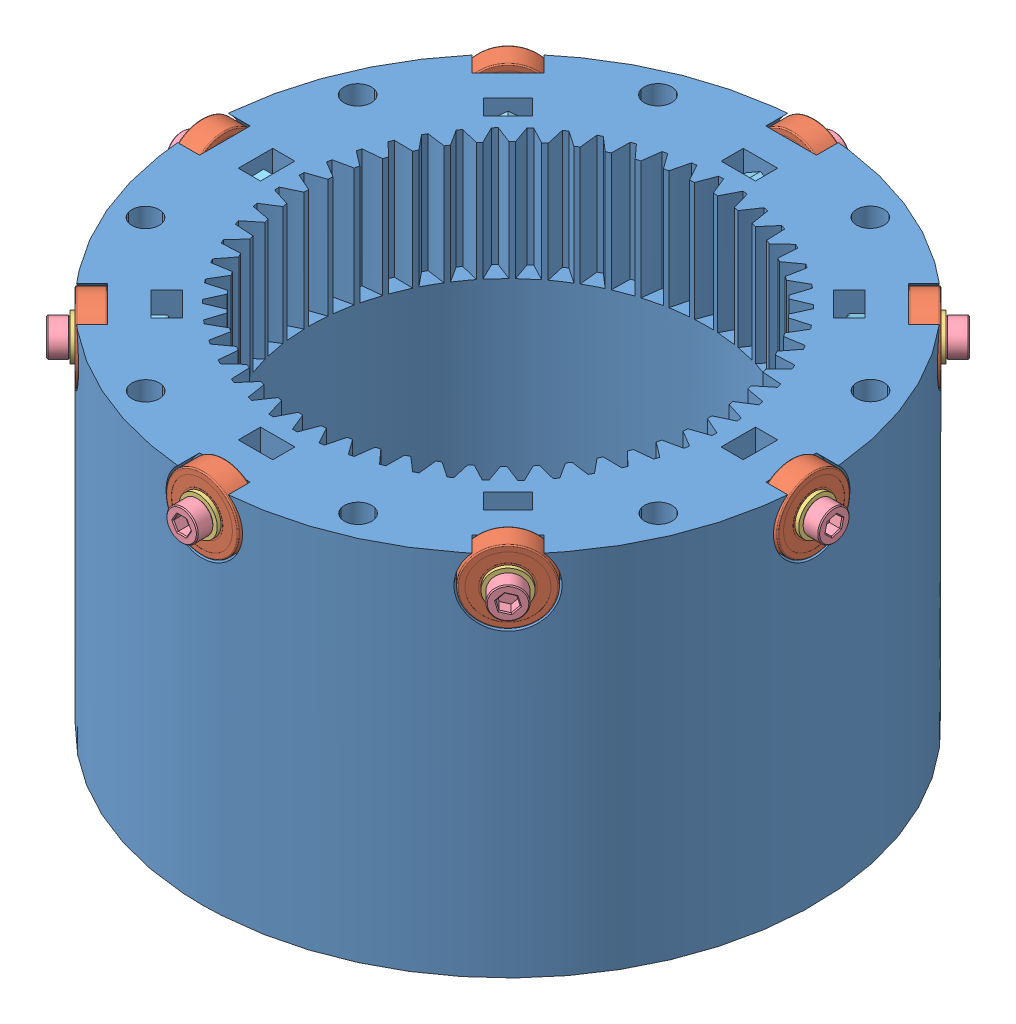
SolidWorks assembly plantery reducer, configuration Default. Lengths in mm.
Overall size (170.6 101.1 170.6).
33 component instances, 5 part files, 96 mates.
Components (placement in the parent):
- updated_1M2A-1: updated_1M2A [Predeterminado] at (8.2264 44.0643 176.7779) size (160 96.57 160)
- 607ZZ-1: 607ZZ [Default] at (60.5523 132.5643 124.452) x (0.707107 0 -0.707107) z (0.642402 -0.417898 0.642402) size (6 19 19)
- 607ZZ-2: 607ZZ [Default] at (8.2264 132.5643 256.7779) x (0 0 -1) z (0.989529 -0.144332 0) size (6 19 19)
- 607ZZ-3: 607ZZ [Default] at (60.5523 132.5643 229.1038) x (0.707107 0 0.707107) z (0.112875 -0.987177 -0.112875) size (6 19 19)
- 607ZZ-4: 607ZZ [Default] at (82.2264 132.5643 176.7779) x (1 0 0) z (0 -0.988196 -0.153195) size (6 19 19)
- 607ZZ-5: 607ZZ [Default] at (-48.3421 132.5643 120.2094) x (0.707107 0 0.707107) z (-0.707107 0 0.707107) size (6 19 19)
- 607ZZ-6: 607ZZ [Default] at (-71.7736 132.5643 176.7779) size (6 19 19)
- 607ZZ-7: 607ZZ [Default] at (-48.3421 132.5643 233.3465) x (0.707107 0 -0.707107) z (0.660156 -0.358314 0.660156) size (6 19 19)
- 607ZZ-8: 607ZZ [Default] at (8.2264 132.5643 96.7779) x (0 0 1) z (-0.997892 0.064889 0) size (6 19 19)
- M5 Rivet Nut-4: M5 Rivet Nut [Default] at (65.5021 132.5643 119.5023) x (0.5 0.707107 0.5) z (0.5 -0.707107 0.5) size (10 13 10)
- M5 Rivet Nut-5: M5 Rivet Nut [Default] at (8.2264 132.5643 95.7779) x (1 0 0) z (0 -1 0) size (10 13 10)
- M5 Rivet Nut-6: M5 Rivet Nut [Default] at (-49.0492 132.5643 119.5023) x (0.5 -0.707107 -0.5) z (-0.5 -0.707107 0.5) size (10 13 10)
- M5 Rivet Nut-7: M5 Rivet Nut [Default] at (89.2264 132.5643 176.7779) x (0 1 0) z (0 0 1) size (10 13 10)
- M5 Rivet Nut-8: M5 Rivet Nut [Default] at (8.2264 132.5643 257.7779) x (1 0 0) z (0 1 0) size (10 13 10)
- M5 Rivet Nut-9: M5 Rivet Nut [Default] at (65.5021 132.5643 234.0536) x (0.5 0.707107 -0.5) z (-0.5 0.707107 0.5) size (10 13 10)
- M5 Rivet Nut-10: M5 Rivet Nut [Default] at (-49.0492 132.5643 234.0536) x (0.5 -0.707107 0.5) z (0.5 0.707107 0.5) size (10 13 10)
- M5 Rivet Nut-11: M5 Rivet Nut [Default] at (-72.7736 132.5643 176.7779) x (0 -1 0) z (0 0 1) size (10 13 10)
- M5x20-1: M5x20 [Predeterminado] at (8.2264 132.5643 91.4779) x (1 0 0) z (0 -1 0) size (8.2 24.3 8.2)
- M5x20-2: M5x20 [Predeterminado] at (68.5426 132.5643 116.4617) x (0.5 0.707107 0.5) z (0.5 -0.707107 0.5) size (8.2 24.3 8.2)
- M5x20-3: M5x20 [Predeterminado] at (-52.0898 132.5643 116.4617) x (0.5 -0.707107 -0.5) z (-0.5 -0.707107 0.5) size (8.2 24.3 8.2)
- M5x20-4: M5x20 [Predeterminado] at (93.5264 132.5643 176.7779) x (0 0.693084 0.720857) z (0 -0.720857 0.693084) size (8.2 24.3 8.2)
- M5x20-5: M5x20 [Predeterminado] at (-77.0736 132.5643 176.7779) x (0 -1 0) z (0 0 1) size (8.2 24.3 8.2)
- M5x20-6: M5x20 [Predeterminado] at (8.2264 132.5643 262.0779) x (1 0 0) z (0 1 0) size (8.2 24.3 8.2)
- M5x20-7: M5x20 [Predeterminado] at (-52.0898 132.5643 237.0941) x (0.5 -0.707107 0.5) z (0.5 0.707107 0.5) size (8.2 24.3 8.2)
- M5x20-8: M5x20 [Predeterminado] at (68.5426 132.5643 237.0941) x (0.5 0.707107 -0.5) z (-0.5 0.707107 0.5) size (8.2 24.3 8.2)
- M5 Lock-1: M5 Lock [Predeterminado] at (8.2264 132.5643 242.7779) x (-0.651073 0.759015 0) z (-0.759015 -0.651073 0) size (7.85 4.3 9.06)
- M5 Lock-2: M5 Lock [Predeterminado] at (74.2264 132.5643 176.7779) x (0 0.785093 -0.619378) z (0 0.619378 0.785093) size (7.85 4.3 9.06)
- M5 Lock-3: M5 Lock [Predeterminado] at (54.8955 132.5643 223.447) x (-0.706997 0.017601 0.706997) z (-0.012446 -0.999845 0.012446) size (7.85 4.3 9.06)
- M5 Lock-4: M5 Lock [Predeterminado] at (54.8955 132.5643 130.1089) x (0.698414 -0.156315 0.698414) z (-0.110531 -0.987707 -0.110531) size (7.85 4.3 9.06)
- M5 Lock-5: M5 Lock [Predeterminado] at (-57.7736 132.5643 176.7779) x (0 -0.99951 -0.031292) z (0 -0.031292 0.99951) size (7.85 4.3 9.06)
- M5 Lock-7: M5 Lock [Predeterminado] at (-38.4426 132.5643 130.1089) x (-0.707095 0.005803 0.707095) z (0.004104 0.999983 -0.004104) size (7.85 4.3 9.06)
- M5 Lock-8: M5 Lock [Predeterminado] at (8.2264 132.5643 110.7779) x (1 0 0) z (0 -1 0) size (7.85 4.3 9.06)
- M5 Lock-9: M5 Lock [Predeterminado] at (-38.4426 132.5643 223.447) x (0.69165 0.207946 0.69165) z (-0.14704 0.97814 -0.14704) size (7.85 4.3 9.06)
Mates (geometry in assembly coordinates):
- Concentric8: concentric anti-aligned: cylinder of planetary gear-3 through (25.4855 152.6206 204.9049) axis (0 -1 0) radius 5.5
- Concentric9: concentric anti-aligned: cylinder of planetary gear-1 through (-24.7736 152.6206 177.6616) axis (0 -1 0) radius 5.5
- Concentric10: concentric anti-aligned: cylinder of planetary gear-2 through (23.9555 152.6206 147.7677) axis (0 -1 0) radius 5.5
- Concentric12: concentric anti-aligned: cylinder of updated_1M2A-1 through (-47.8741 132.5643 176.7779) axis (-1 0 0) radius 3.5; cylinder of 607ZZ-6 through (-65.7736 132.5643 176.7779) axis (1 0 0) radius 3.5
- Coincident13: coincident anti-aligned: plane of updated_1M2A-1 through (-65.7736 132.5643 176.7779) normal (-1 0 0); plane of 607ZZ-6 through (-65.7736 136.3643 176.7779) normal (1 0 0)
- Concentric13: concentric anti-aligned: cylinder of updated_1M2A-1 through (-31.4426 132.5643 216.447) axis (-0.707107 0 0.707107) radius 3.5; cylinder of 607ZZ-7 through (-44.0995 132.5643 229.1038) axis (0.707107 0 -0.707107) radius 3.5
- Coincident14: coincident anti-aligned: plane of updated_1M2A-1 through (-44.0995 132.5643 229.1038) normal (-0.707107 0 0.707107); plane of 607ZZ-7 through (-43.1367 136.112 230.0666) normal (0.707107 0 -0.707107)
- Concentric14: concentric anti-aligned: cylinder of updated_1M2A-1 through (8.2264 132.5643 232.8784) axis (0 0 1) radius 3.5; cylinder of 607ZZ-2 through (8.2264 132.5643 250.7779) axis (0 0 -1) radius 3.5
- Coincident15: coincident anti-aligned: plane of updated_1M2A-1 through (8.2264 132.5643 250.7779) normal (0 0 1); plane of 607ZZ-2 through (8.7749 136.3245 250.7779) normal (0 0 -1)
- Concentric15: concentric aligned: cylinder of updated_1M2A-1 through (47.8955 132.5643 216.447) axis (0.707107 0 0.707107) radius 3.5; cylinder of 607ZZ-3 through (64.795 132.5643 233.3465) axis (0.707107 0 0.707107) radius 3.5
- Coincident16: coincident anti-aligned: plane of updated_1M2A-1 through (60.5523 132.5643 229.1038) normal (0.707107 0 0.707107); plane of 607ZZ-3 through (56.769 131.6991 232.8872) normal (-0.707107 0 -0.707107)
- Concentric16: concentric aligned: cylinder of updated_1M2A-1 through (64.3269 132.5643 176.7779) axis (1 0 0) radius 3.5; cylinder of 607ZZ-4 through (88.2264 132.5643 176.7779) axis (1 0 0) radius 3.5
- Coincident17: coincident anti-aligned: plane of updated_1M2A-1 through (82.2264 132.5643 176.7779) normal (1 0 0); plane of 607ZZ-4 through (82.2264 131.734 182.134) normal (-1 0 0)
- Concentric17: concentric aligned: cylinder of updated_1M2A-1 through (47.8955 132.5643 137.1089) axis (0.707107 0 -0.707107) radius 3.5; cylinder of 607ZZ-1 through (64.795 132.5643 120.2094) axis (0.707107 0 -0.707107) radius 3.5
- Coincident18: coincident anti-aligned: plane of updated_1M2A-1 through (60.5523 132.5643 124.452) normal (0.707107 0 -0.707107); plane of 607ZZ-1 through (62.1539 137.4883 126.0536) normal (-0.707107 0 0.707107)
- Concentric18: concentric anti-aligned: cylinder of updated_1M2A-1 through (8.2264 132.5643 120.6774) axis (0 0 -1) radius 3.5; cylinder of 607ZZ-8 through (8.2264 132.5643 102.7779) axis (0 0 1) radius 3.5
- Coincident19: coincident anti-aligned: plane of updated_1M2A-1 through (8.2264 132.5643 102.7779) normal (0 0 -1); plane of 607ZZ-8 through (8.473 136.3563 102.7779) normal (0 0 1)
- Coincident20: coincident anti-aligned: plane of updated_1M2A-1 through (-44.0995 132.5643 124.452) normal (-0.707107 0 -0.707107); plane of 607ZZ-5 through (-44.0995 136.3643 124.452) normal (0.707107 0 0.707107)
- Concentric19: concentric anti-aligned: cylinder of updated_1M2A-1 through (-31.4426 132.5643 137.1089) axis (-0.707107 0 -0.707107) radius 3.5; cylinder of 607ZZ-5 through (-44.0995 132.5643 124.452) axis (0.707107 0 0.707107) radius 3.5
- Concentric20: concentric anti-aligned: cylinder of planetary gear-1 through (-24.7736 152.6206 177.6616) axis (0 -1 0) radius 5.5; cylinder of 607ZZ-9 through (-24.7736 135.0643 177.6616) axis (0 1 0) radius 3.5
- Coincident21: coincident anti-aligned: plane of planetary gear-1 through (-24.7736 135.0643 177.6616) normal (0 -1 0); plane of 607ZZ-9 through (-28.5736 135.0643 177.6616) normal (0 1 0)
- Concentric21: concentric anti-aligned: cylinder of planetary gear-3 through (25.4855 152.6206 204.9049) axis (0 -1 0) radius 5.5; cylinder of 607ZZ-11 through (25.4855 135.0643 204.9049) axis (0 1 0) radius 3.5
- Coincident22: coincident anti-aligned: plane of planetary gear-3 through (25.4855 135.0643 204.9049) normal (0 -1 0); plane of 607ZZ-11 through (25.1384 135.0643 208.689) normal (0 1 0)
- Concentric22: concentric anti-aligned: cylinder of planetary gear-2 through (23.9555 152.6206 147.7677) axis (0 -1 0) radius 5.5; cylinder of 607ZZ-10 through (23.9555 135.0973 147.7677) axis (0 1 0) radius 3.5
- Coincident27: coincident anti-aligned: plane of planetary gear-2 through (23.9555 135.0643 147.7677) normal (0 -1 0); plane of 607ZZ-10 through (21.028 135.0643 143.2064) normal (0 1 0)
- Concentric23: concentric anti-aligned: cylinder of 607ZZ-11 through (25.4855 135.0643 204.9049) axis (0 1 0) radius 3.5; cylinder of 607ZZ-12 through (25.4855 123.0643 204.9049) axis (0 -1 0) radius 3.5
- Coincident28: coincident anti-aligned: plane of 607ZZ-11 through (24.9905 129.0643 210.3022) normal (0 -1 0); plane of 607ZZ-12 through (30.9055 129.0643 204.9049) normal (0 1 0)
- Concentric24: concentric anti-aligned: cylinder of 607ZZ-10 through (23.9555 135.0973 147.7677) axis (0 1 0) radius 3.5; cylinder of 607ZZ-13 through (23.9555 123.0973 147.7677) axis (0 -1 0) radius 3.5
- Coincident29: coincident anti-aligned: plane of 607ZZ-10 through (21.028 129.0973 143.2064) normal (0 -1 0); plane of 607ZZ-13 through (29.3755 129.0973 147.7677) normal (0 1 0)
- Concentric25: concentric anti-aligned: cylinder of 607ZZ-9 through (-24.7736 135.0643 177.6616) axis (0 1 0) radius 3.5; cylinder of 607ZZ-14 through (-24.7736 123.0643 177.6616) axis (0 -1 0) radius 3.5
- Coincident30: coincident anti-aligned: plane of 607ZZ-9 through (-30.1936 129.0643 177.6616) normal (0 -1 0); plane of 607ZZ-14 through (-19.3536 129.0643 177.6616) normal (0 1 0)
- Coincident31: coincident anti-aligned: plane of 607ZZ-9 through (-28.5736 135.0643 177.6616) normal (0 1 0); plane of M5 Rivet Nut-1 through (-24.7736 135.0643 177.6616) normal (0 -1 0)
- Concentric26: concentric aligned: cylinder of 607ZZ-9 through (-24.7736 135.0643 177.6616) axis (0 1 0) radius 3.5; cylinder of M5 Rivet Nut-1 through (-24.7736 123.0643 177.6616) axis (0 1 0) radius 3.5
- Coincident32: coincident anti-aligned: plane of 607ZZ-10 through (21.903 135.0973 144.5697) normal (0 1 0); plane of M5 Rivet Nut-2 through (23.9555 135.0973 147.7677) normal (0 -1 0)
- Concentric27: concentric aligned: cylinder of 607ZZ-10 through (23.9555 135.0973 147.7677) axis (0 1 0) radius 3.5; cylinder of M5 Rivet Nut-2 through (23.9555 123.0973 147.7677) axis (0 1 0) radius 3.5
- Coincident34: coincident anti-aligned: plane of 607ZZ-11 through (25.1384 135.0643 208.689) normal (0 1 0); plane of M5 Rivet Nut-3 through (25.4855 135.0643 204.9049) normal (0 -1 0)
- Concentric28: concentric aligned: cylinder of 607ZZ-11 through (25.4855 135.0643 204.9049) axis (0 1 0) radius 3.5; cylinder of M5 Rivet Nut-3 through (25.4855 123.0643 204.9049) axis (0 1 0) radius 3.5
- Distance1: distance = 3 mm aligned: plane of planetary gear-1 through (-24.7736 137.0643 177.6616) normal (0 1 0); plane of updated_1M2A-1 through (8.2264 140.0643 176.7779) normal (0 1 0)
- Distance2: distance = 3 mm aligned: plane of planetary gear-3 through (25.4855 137.0643 204.9049) normal (0 1 0); plane of updated_1M2A-1 through (8.2264 140.0643 176.7779) normal (0 1 0)
- Distance3: distance = 3 mm aligned: plane of planetary gear-2 through (23.9555 137.0643 147.7677) normal (0 1 0); plane of updated_1M2A-1 through (8.2264 140.0643 176.7779) normal (0 1 0)
- Coincident39: coincident anti-aligned: plane of 607ZZ-4 through (88.2264 131.9822 180.5331) normal (1 0 0); plane of M5 Rivet Nut-7 through (88.2264 132.5643 176.7779) normal (-1 0 0)
- Concentric29: concentric anti-aligned: cylinder of updated_1M2A-1 through (64.3269 132.5643 176.7779) axis (1 0 0) radius 3.5; cylinder of M5 Rivet Nut-7 through (96.2975 132.5643 176.7779) axis (-1 0 0) radius 2.5
- Coincident40: coincident anti-aligned: plane of 607ZZ-1 through (65.9179 136.0166 121.3323) normal (0.707107 0 -0.707107); plane of M5 Rivet Nut-4 through (64.795 132.5643 120.2094) normal (-0.707107 0 0.707107)
- Concentric30: concentric anti-aligned: cylinder of 607ZZ-1 through (64.795 132.5643 120.2094) axis (0.707107 0 -0.707107) radius 3.5; cylinder of M5 Rivet Nut-4 through (70.5021 132.5643 114.5023) axis (-0.707107 0 0.707107) radius 2.5
- Coincident41: coincident anti-aligned: plane of 607ZZ-8 through (8.5781 137.9729 96.7779) normal (0 0 -1); plane of M5 Rivet Nut-5 through (8.2264 132.5643 96.7779) normal (0 0 1)
- Concentric31: concentric aligned: cylinder of 607ZZ-8 through (8.2264 132.5643 102.7779) axis (0 0 1) radius 3.5; cylinder of M5 Rivet Nut-5 through (8.2264 132.5643 88.7069) axis (0 0 1) radius 2.5
- Coincident42: coincident anti-aligned: plane of 607ZZ-5 through (-48.3421 137.9843 120.2094) normal (-0.707107 0 -0.707107); plane of M5 Rivet Nut-6 through (-48.3421 132.5643 120.2094) normal (0.707107 0 0.707107)
- Concentric32: concentric aligned: cylinder of 607ZZ-5 through (-44.0995 132.5643 124.452) axis (0.707107 0 0.707107) radius 3.5; cylinder of M5 Rivet Nut-6 through (-54.0492 132.5643 114.5023) axis (0.707107 0 0.707107) radius 2.5
- Coincident43: coincident anti-aligned: plane of 607ZZ-6 through (-71.7736 137.9843 176.7779) normal (-1 0 0); plane of M5 Rivet Nut-11 through (-71.7736 132.5643 176.7779) normal (1 0 0)
- Concentric33: concentric aligned: cylinder of 607ZZ-6 through (-65.7736 132.5643 176.7779) axis (1 0 0) radius 3.5; cylinder of M5 Rivet Nut-11 through (-79.8446 132.5643 176.7779) axis (1 0 0) radius 2.5
- Coincident44: coincident anti-aligned: plane of 607ZZ-7 through (-46.9689 137.6244 234.7197) normal (-0.707107 0 0.707107); plane of M5 Rivet Nut-10 through (-48.3421 132.5643 233.3465) normal (0.707107 0 -0.707107)
- Concentric34: concentric aligned: cylinder of 607ZZ-7 through (-44.0995 132.5643 229.1038) axis (0.707107 0 -0.707107) radius 3.5; cylinder of M5 Rivet Nut-10 through (-54.0492 132.5643 239.0536) axis (0.707107 0 -0.707107) radius 2.5
- Coincident45: coincident anti-aligned: plane of 607ZZ-2 through (9.0087 137.9275 256.7779) normal (0 0 1); plane of M5 Rivet Nut-8 through (8.2264 132.5643 256.7779) normal (0 0 -1)
- Concentric35: concentric aligned: cylinder of 607ZZ-2 through (8.2264 132.5643 250.7779) axis (0 0 -1) radius 3.5; cylinder of M5 Rivet Nut-8 through (8.2264 132.5643 264.849) axis (0 0 -1) radius 2.5
- Coincident46: coincident anti-aligned: plane of 607ZZ-3 through (62.1424 131.9577 235.999) normal (0.707107 0 0.707107); plane of M5 Rivet Nut-9 through (64.795 132.5643 233.3465) normal (-0.707107 0 -0.707107)
- Concentric36: concentric anti-aligned: cylinder of 607ZZ-3 through (64.795 132.5643 233.3465) axis (0.707107 0 0.707107) radius 3.5; cylinder of M5 Rivet Nut-9 through (70.5021 132.5643 239.0536) axis (-0.707107 0 -0.707107) radius 2.5
- Coincident47: coincident anti-aligned: plane of M5 Rivet Nut-6 through (-49.0492 132.5643 119.5023) normal (-0.707107 0 -0.707107); plane of M5x22-3 through (-49.0492 126.5643 119.5023) normal (0.707107 0 0.707107)
- Concentric37: concentric anti-aligned: cylinder of M5 Rivet Nut-6 through (-54.0492 132.5643 114.5023) axis (0.707107 0 0.707107) radius 2.5; cylinder of M5x22-3 through (-33.4929 126.5643 135.0586) axis (-0.707107 0 -0.707107) radius 2.35
- Coincident48: coincident anti-aligned: plane of M5 Rivet Nut-10 through (-49.0492 132.5643 234.0536) normal (-0.707107 0 0.707107); plane of M5x20-7 through (-49.0492 132.5643 234.0536) normal (0.707107 0 -0.707107)
- Concentric39: concentric anti-aligned: cylinder of M5 Rivet Nut-10 through (-54.0492 132.5643 239.0536) axis (0.707107 0 -0.707107) radius 2.5; cylinder of M5x20-7 through (-34.9071 132.5643 219.9114) axis (-0.707107 0 0.707107) radius 2.35
- Coincident49: coincident anti-aligned: plane of M5 Rivet Nut-8 through (8.2264 132.5643 257.7779) normal (0 0 1); plane of M5x20-6 through (8.2264 132.5643 257.7779) normal (0 0 -1)
- Concentric40: concentric aligned: cylinder of updated_1M2A-1 through (8.2264 132.5643 232.8784) axis (0 0 1) radius 3.5; cylinder of M5x20-6 through (8.2264 132.5643 237.7779) axis (0 0 1) radius 2.35
- Coincident50: coincident anti-aligned: plane of M5 Rivet Nut-9 through (65.5021 132.5643 234.0536) normal (0.707107 0 0.707107); plane of M5x20-8 through (65.5021 132.5643 234.0536) normal (-0.707107 0 -0.707107)
- Concentric41: concentric anti-aligned: cylinder of M5 Rivet Nut-9 through (70.5021 132.5643 239.0536) axis (-0.707107 0 -0.707107) radius 2.5; cylinder of M5x20-8 through (51.3599 132.5643 219.9114) axis (0.707107 0 0.707107) radius 2.35
- Coincident51: coincident anti-aligned: plane of M5 Rivet Nut-7 through (89.2264 132.5643 176.7779) normal (1 0 0); plane of M5x20-4 through (89.2264 132.5643 176.7779) normal (-1 0 0)
- Concentric42: concentric anti-aligned: cylinder of M5 Rivet Nut-7 through (96.2975 132.5643 176.7779) axis (-1 0 0) radius 2.5; cylinder of M5x20-4 through (69.2264 132.5643 176.7779) axis (1 0 0) radius 2.35
- Coincident52: coincident anti-aligned: plane of M5 Rivet Nut-4 through (65.5021 132.5643 119.5023) normal (0.707107 0 -0.707107); plane of M5x20-2 through (65.5021 132.5643 119.5023) normal (-0.707107 0 0.707107)
- Concentric43: concentric anti-aligned: cylinder of M5 Rivet Nut-4 through (70.5021 132.5643 114.5023) axis (-0.707107 0 0.707107) radius 2.5; cylinder of M5x20-2 through (51.3599 132.5643 133.6444) axis (0.707107 0 -0.707107) radius 2.35
- Coincident53: coincident anti-aligned: plane of M5 Rivet Nut-5 through (8.2264 132.5643 95.7779) normal (0 0 -1); plane of M5x20-1 through (8.2264 132.5643 95.7779) normal (0 0 1)
- Concentric44: concentric anti-aligned: cylinder of M5 Rivet Nut-5 through (8.2264 132.5643 88.7069) axis (0 0 1) radius 2.5; cylinder of M5x20-1 through (8.2264 132.5643 115.7779) axis (0 0 -1) radius 2.35
- Coincident54: coincident anti-aligned: plane of M5 Rivet Nut-6 through (-49.0492 132.5643 119.5023) normal (-0.707107 0 -0.707107); plane of M5x20-3 through (-49.0492 132.5643 119.5023) normal (0.707107 0 0.707107)
- Concentric45: concentric anti-aligned: cylinder of M5 Rivet Nut-6 through (-54.0492 132.5643 114.5023) axis (0.707107 0 0.707107) radius 2.5; cylinder of M5x20-3 through (-34.9071 132.5643 133.6444) axis (-0.707107 0 -0.707107) radius 2.35
- Coincident55: coincident anti-aligned: plane of M5 Rivet Nut-11 through (-72.7736 132.5643 176.7779) normal (-1 0 0); plane of M5x20-5 through (-72.7736 132.5643 176.7779) normal (1 0 0)
- Concentric46: concentric anti-aligned: cylinder of M5 Rivet Nut-11 through (-79.8446 132.5643 176.7779) axis (1 0 0) radius 2.5; cylinder of M5x20-5 through (-52.7736 132.5643 176.7779) axis (-1 0 0) radius 2.35
- Coincident56: coincident anti-aligned: plane of updated_1M2A-1 through (12.7264 126.9643 242.7779) normal (0 0 -1); plane of M5 Lock-1 through (8.2264 132.5643 242.7779) normal (0 0 1)
- Concentric48: concentric aligned: cylinder of M5x20-6 through (8.2264 132.5643 237.7779) axis (0 0 1) radius 2.35; cylinder of M5 Lock-1 through (8.2264 132.5643 211.7779) axis (0 0 1) radius 2.5
- Concentric49: concentric aligned: cylinder of M5x20-8 through (51.3599 132.5643 219.9114) axis (0.707107 0 0.707107) radius 2.35; circle of M5 Lock-3
- Coincident58: coincident anti-aligned: plane of updated_1M2A-1 through (58.0775 126.9643 220.265) normal (-0.707107 0 -0.707107); plane of M5 Lock-3 through (54.8955 132.5643 223.447) normal (0.707107 0 0.707107)
- Concentric51: concentric aligned: cylinder of M5x20-4 through (69.2264 132.5643 176.7779) axis (1 0 0) radius 2.35; cylinder of M5 Lock-2 through (43.2264 132.5643 176.7779) axis (1 0 0) radius 2.5
- Coincident59: coincident anti-aligned: plane of updated_1M2A-1 through (74.2264 126.9643 172.2779) normal (-1 0 0); plane of M5 Lock-2 through (74.2264 132.5643 176.7779) normal (1 0 0)
- Concentric52: concentric aligned: cylinder of M5x20-5 through (-52.7736 132.5643 176.7779) axis (-1 0 0) radius 2.35; cylinder of M5 Lock-5 through (-26.7736 132.5643 176.7779) axis (-1 0 0) radius 2.5
- Coincident60: coincident anti-aligned: plane of updated_1M2A-1 through (-57.7736 126.9643 181.2779) normal (1 0 0); plane of M5 Lock-5 through (-57.7736 132.5643 176.7779) normal (-1 0 0)
- Concentric53: concentric aligned: cylinder of M5x20-7 through (-34.9071 132.5643 219.9114) axis (-0.707107 0 0.707107) radius 2.35; cylinder of M5 Lock-9 through (-16.5223 132.5643 201.5267) axis (-0.707107 0 0.707107) radius 2.5
- Coincident61: coincident anti-aligned: plane of updated_1M2A-1 through (-35.2606 126.9643 226.629) normal (0.707107 0 -0.707107); plane of M5 Lock-9 through (-38.4426 132.5643 223.447) normal (-0.707107 0 0.707107)
- Concentric54: concentric aligned: cylinder of M5x20-3 through (-34.9071 132.5643 133.6444) axis (-0.707107 0 -0.707107) radius 2.35; cylinder of M5 Lock-7 through (-16.5223 132.5643 152.0292) axis (-0.707107 0 -0.707107) radius 2.5
- Coincident63: coincident anti-aligned: plane of updated_1M2A-1 through (-41.6246 126.9643 133.2909) normal (0.707107 0 0.707107); plane of M5 Lock-7 through (-38.4426 132.5643 130.1089) normal (-0.707107 0 -0.707107)
- Coincident64: coincident anti-aligned: plane of updated_1M2A-1 through (3.7264 126.9643 110.7779) normal (0 0 1); plane of M5 Lock-8 through (8.2264 132.5643 110.7779) normal (0 0 -1)
- Concentric56: concentric aligned: cylinder of M5x20-1 through (8.2264 132.5643 115.7779) axis (0 0 -1) radius 2.35; cylinder of M5 Lock-8 through (8.2264 132.5643 141.7779) axis (0 0 -1) radius 2.5
- Concentric57: concentric aligned: cylinder of M5x20-2 through (51.3599 132.5643 133.6444) axis (0.707107 0 -0.707107) radius 2.35; cylinder of M5 Lock-4 through (32.9752 132.5643 152.0292) axis (0.707107 0 -0.707107) radius 2.5
- Coincident65: coincident anti-aligned: plane of updated_1M2A-1 through (51.7135 126.9643 126.9269) normal (-0.707107 0 0.707107); plane of M5 Lock-4 through (54.8955 132.5643 130.1089) normal (0.707107 0 -0.707107)
- Coincident68: coincident anti-aligned: plane of 607ZZ-12 through (30.9055 123.0973 204.9049) normal (0 -1 0); plane of bearing cover V3-1 through (25.4855 123.0973 204.9049) normal (0 1 0)
- Concentric60: concentric aligned: cylinder of planetary gear-3 through (25.4855 135.0643 204.9049) axis (0 -1 0) radius 9.725; cylinder of bearing cover V3-1 through (25.4855 123.0973 204.9049) axis (0 -1 0) radius 6.5
- Coincident69: coincident anti-aligned: plane of 607ZZ-14 through (-19.3536 123.0973 177.6616) normal (0 -1 0); plane of bearing cover V3-3 through (-24.7736 123.0973 177.6616) normal (0 1 0)
- Concentric61: concentric aligned: cylinder of planetary gear-1 through (-24.7736 135.0643 177.6616) axis (0 -1 0) radius 9.725; cylinder of bearing cover V3-3 through (-24.7736 123.0973 177.6616) axis (0 -1 0) radius 6.5
- Coincident70: coincident anti-aligned: plane of 607ZZ-13 through (29.3755 123.1303 147.7677) normal (0 -1 0); plane of bearing cover V3-2 through (23.9555 123.1303 147.7677) normal (0 1 0)
- Concentric62: concentric aligned: cylinder of planetary gear-2 through (23.9555 135.0643 147.7677) axis (0 -1 0) radius 9.725; cylinder of bearing cover V3-2 through (23.9555 123.1303 147.7677) axis (0 -1 0) radius 6.5
